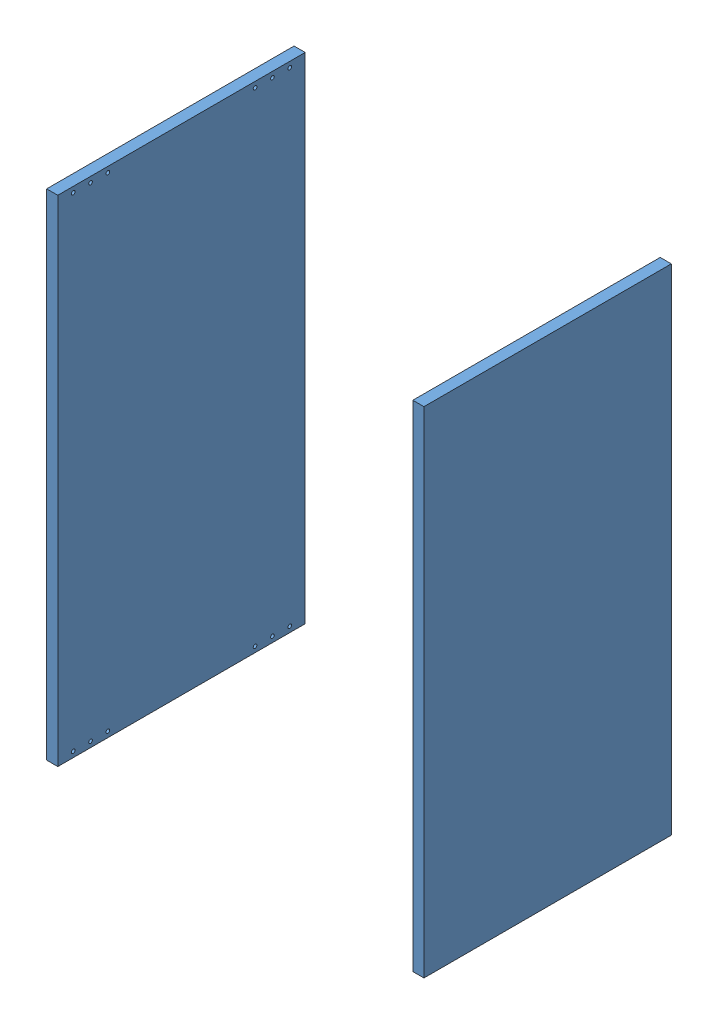
SolidWorks assembly ШкафНП1Сб, configuration По умолчанию. Lengths in mm.
Overall size (610 800 400).
2 component instances, 1 part files, 3 mates.
Components (placement in the parent):
- БокНПП-1: БокНПП [По умолчанию] at (0 0 -450) x (0 0 1) z (0 -1 0) size (400 18 800)
- БокНПП-2: БокНПП [По умолчанию] at (-610 0 -50) x (0 0 -1) z (0 -1 0) size (400 18 800)
Mates (geometry in assembly coordinates):
- Совпадение4: coincident aligned: plane of БокНПП-1 through (-18 800 -450) normal (0 1 0); plane of БокНПП-2 through (-532 800 -50) normal (0 1 0)
- Расстояние1: distance = 610 mm anti-aligned: plane of БокНПП-1 through (0 0 -450) normal (1 0 0); plane of БокНПП-2 through (-610 0 -50) normal (-1 0 0)
- Совпадение6: coincident aligned: plane of БокНПП-1 through (-18 0 -50) normal (0 0 1); plane of БокНПП-2 through (-532 0 -50) normal (0 0 1)
